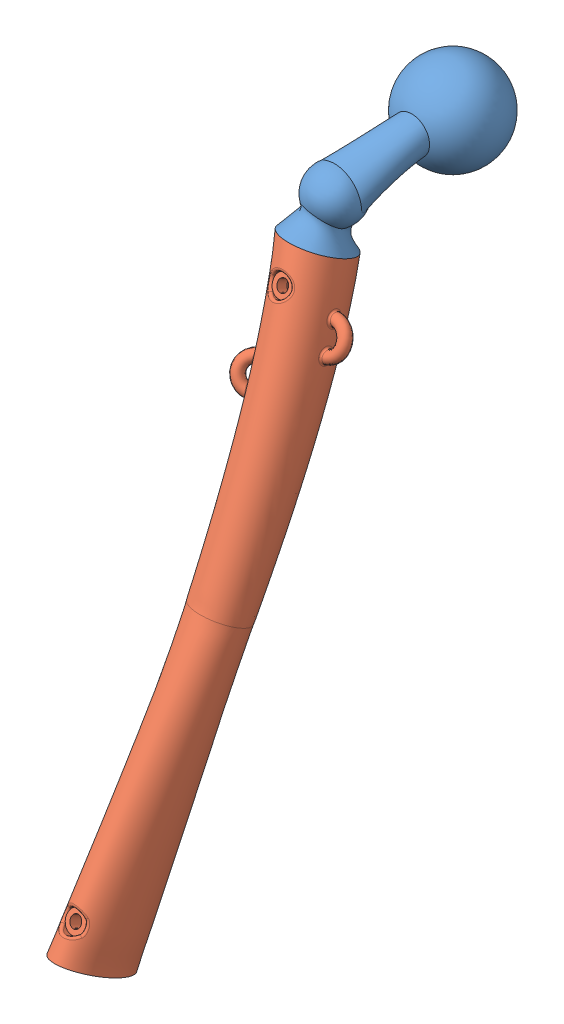
SolidWorks assembly sizing, configuration Default. Lengths in mm.
Overall size (283.3 440.81 311.8).
2 component instances, 2 part files, 0 mates.
Components (placement in the parent):
- ball3-1: ball3 [Default] at (-235.6638 189.8732 118.9813) x (0.994678 -0.102885 0.005583) z (-0.007911 -0.022231 0.999722) size (50.94 72.58 104.64)
- femor bone mirror-1: femor bone mirror [Default] at (-257.4717 -244.5471 353.1293) x (-0.996439 0.009355 -0.083801) z (-0.075176 0.3516 0.933127) size (63.87 307.72 68.31)
